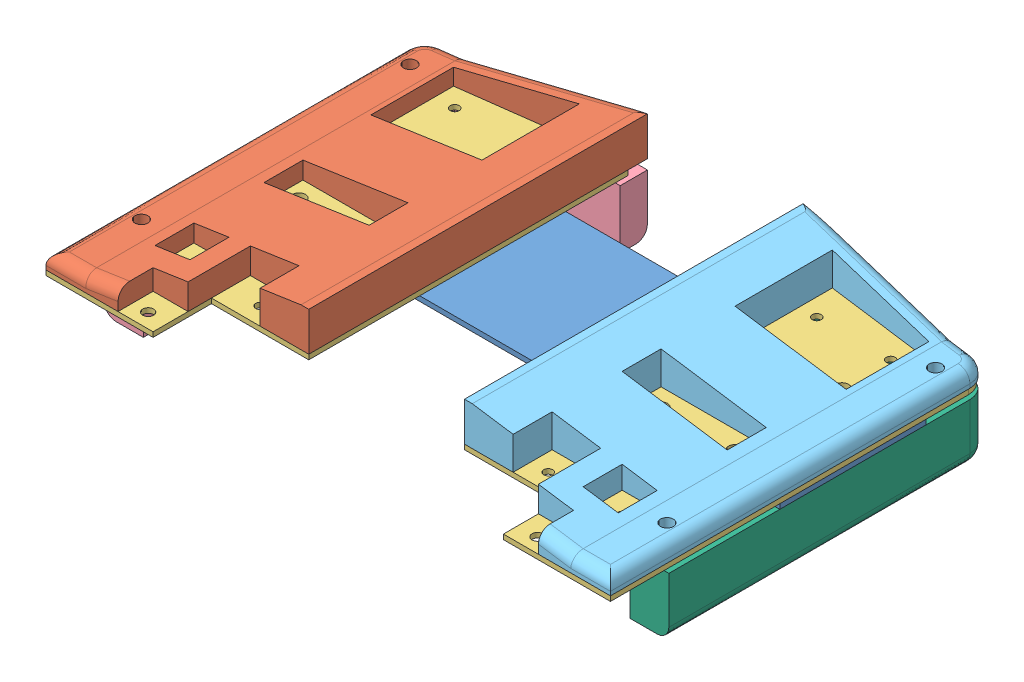
SolidWorks assembly UMPC, configuration Default. Lengths in mm.
Overall size (145 27.5 102).
7 component instances, 6 part files, 5 mates.
Components (placement in the parent):
- horizontal metal frame-1: horizontal metal frame [Default] at (50.6126 35.4075 84.9189) size (145 1.25 37.5)
- Lid-1: Lid [Default] at (52.4534 37.9075 81.9601) size (52.5 10 102)
- Vertical Metal Frame-2: Vertical Metal Frame [Default] at (-6.2324 36.6575 113.054) size (52.5 1.25 97)
- Front Bezel-1: Front Bezel [Default] at (19.3315 20.4075 91.8908) size (52.5 15 87)
- Lid1-2: Lid1 [Default] at (50.6548 37.9075 81.9601) x (-1 0 0) z (0 0 -1) size (52.5 10 102)
- Vertical Metal Frame-3: Vertical Metal Frame [Default] at (109.3406 37.9075 113.054) x (-1 0 0) z (0 0 1) size (52.5 1.25 97)
- MirrorFront Bezel-2: MirrorFront Bezel [Default] at (83.7767 20.4075 91.8908) x (-1 0 0) z (0 0 -1) size (52.5 15 87)
Mates (geometry in assembly coordinates):
- Concentric1: concentric: circle of horizontal metal frame-1; circle of Vertical Metal Frame-2
- Coincident2: coincident: line of horizontal metal frame-1 through (-20.9459 36.6575 54.8441) axis (0 0 1); line of Vertical Metal Frame-2 through (-20.9459 36.6575 43.8441) axis (0 0 1)
- Coincident3: coincident: circle of Lid-1; circle of Vertical Metal Frame-2
- Concentric2: concentric: circle of Vertical Metal Frame-2; circle of Front Bezel-1
- Coincident8: coincident: plane of horizontal metal frame-1 through (50.6126 35.4075 84.9189) normal (0 -1 0); plane of Front Bezel-1 through (19.3315 35.4075 91.8908) normal (0 1 0)
